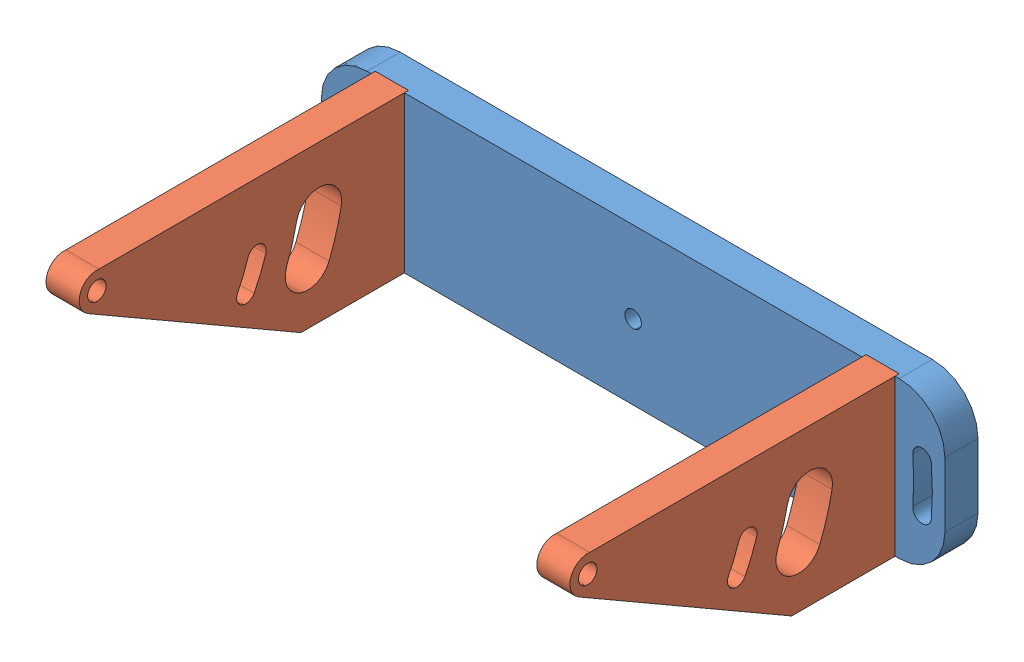
SolidWorks assembly LMBrace_P2_V2, configuration Default. Lengths in mm.
Overall size (150.53 37.7 86.52).
3 component instances, 2 part files, 6 mates.
Components (placement in the parent):
- LMBrace_P21_V2-1: LMBrace_P21_V2 [Default] at (-80.8704 1.5862 3.0045) size (150.53 37.67 8)
- LMBrace_P22_V2-1: LMBrace_P22_V2 [Default] at (-75.8704 1.5862 7.0045) size (8 37.7 79.52)
- LMBrace_P22_V2-2: LMBrace_P22_V2 [Default] at (42.6296 1.5862 7.0045) size (8 37.7 79.52)
Mates (geometry in assembly coordinates):
- Concentric1: concentric aligned: cylinder of LMBrace_P21_V2-1 through (-79.8704 30.9211 -0.9955) axis (0 0 -1) radius 2.75; cylinder of LMBrace_P22_V2-1 through (-79.8704 30.9211 6.0045) axis (0 0 -1) radius 2.1
- Concentric2: concentric aligned: cylinder of LMBrace_P22_V2-1 through (-79.8704 5.9211 6.0045) axis (0 0 -1) radius 2.1; cylinder of LMBrace_P21_V2-1 through (-79.8704 5.9211 -0.9955) axis (0 0 -1) radius 2.75
- Coincident2: coincident anti-aligned: plane of LMBrace_P21_V2-1 through (-80.8704 1.5862 6.0045) normal (0 0 1); plane of LMBrace_P22_V2-1 through (-75.8704 1.5862 6.0045) normal (0 0 -1)
- Concentric3: concentric: cylinder of LMBrace_P21_V2-1 through (38.6296 30.9211 -0.9955) axis (0 0 -1) radius 2.75; cylinder of LMBrace_P22_V2-2 through (38.6296 30.9211 2.0045) axis (0 0 -1) radius 2.1
- Concentric4: concentric: cylinder of LMBrace_P21_V2-1 through (38.6296 5.9211 -0.9955) axis (0 0 -1) radius 2.75; cylinder of LMBrace_P22_V2-2 through (38.6296 5.9211 2.0045) axis (0 0 -1) radius 2.1
- Coincident3: coincident anti-aligned: plane of LMBrace_P21_V2-1 through (-80.8704 1.5862 6.0045) normal (0 0 1); plane of LMBrace_P22_V2-2 through (42.6296 1.5862 6.0045) normal (0 0 -1)
